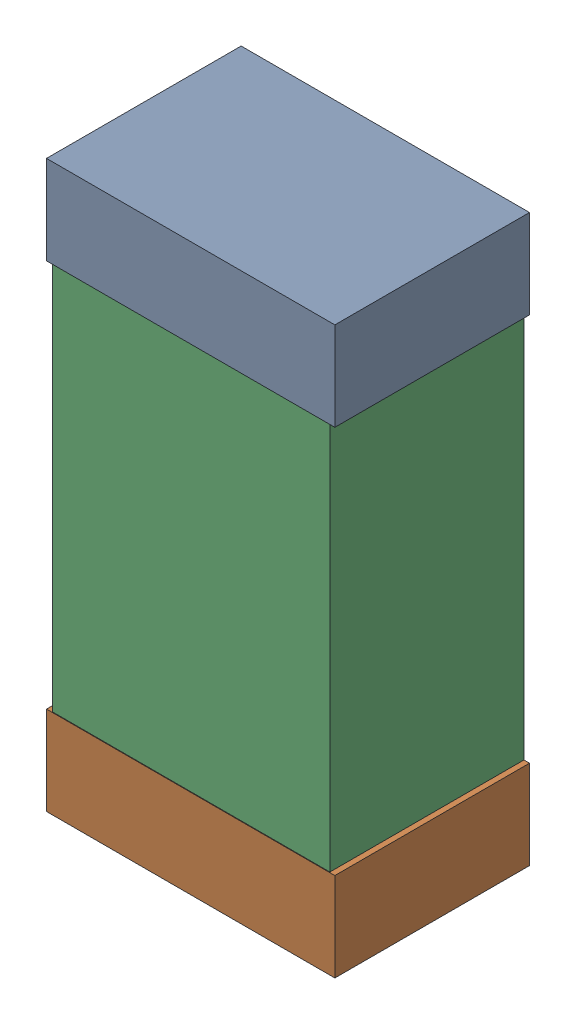
SolidWorks assembly C15, configuration Default. Lengths in mm.
Overall size (0.52 1.02 0.35).
6 component instances, 2 part files, 0 mates.
Components (placement in the parent):
- 870941120-1: 870941120 [Default] at (51.6628 25.4722 0) size (0.52 0.16 0.35)
  - Extruded_3-1: Extruded_3 [Default] at origin size (0.52 0.16 0.35)
- 870941120-2: 870941120 [Default] at (51.6628 24.6122 0) size (0.52 0.16 0.35)
  - Extruded_3-1: Extruded_3 [Default] at origin size (0.52 0.16 0.35)
- 870941280-1: 870941280 [Default] at (51.6628 25.0422 0) size (0.5 1 0.35)
  - Extruded_4-1: Extruded_4 [Default] at origin size (0.5 1 0.35)
